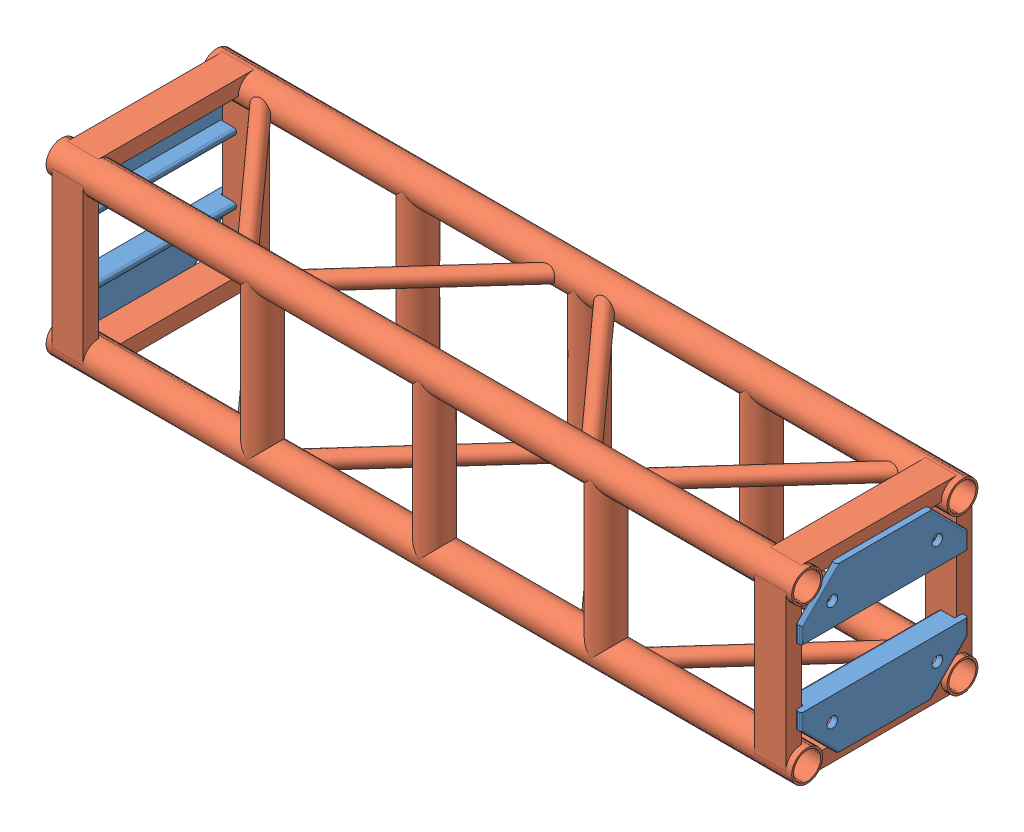
SolidWorks assembly GE-20003, configuration Default. Lengths in mm.
Overall size (1219.2 304.8 304.81).
5 component instances, 2 part files, 0 mates.
Components (placement in the parent):
- Connection Plate _ TS Standard-1: Connection Plate _ TS Standard [Default] at (-592.1375 -90.7415 0) x (0 0 -1) z (1 0 0) size (273.05 85.72 34.92)
- Connection Plate _ TS Standard-2: Connection Plate _ TS Standard [Default] at (-592.1375 90.7415 0) x (0 0 1) z (1 0 0) size (273.05 85.72 34.92)
- Connection Plate _ TS Standard-3: Connection Plate _ TS Standard [Default] at (592.1375 90.7415 0) x (0 0 -1) z (-1 0 0) size (273.05 85.72 34.92)
- Connection Plate _ TS Standard-4: Connection Plate _ TS Standard [Default] at (592.1375 -90.7415 0) x (0 0 1) z (-1 0 0) size (273.05 85.72 34.92)
- GE-20003 - 01-1: GE-20003 - 01 [Default] at origin size (1219.2 304.8 304.81)
